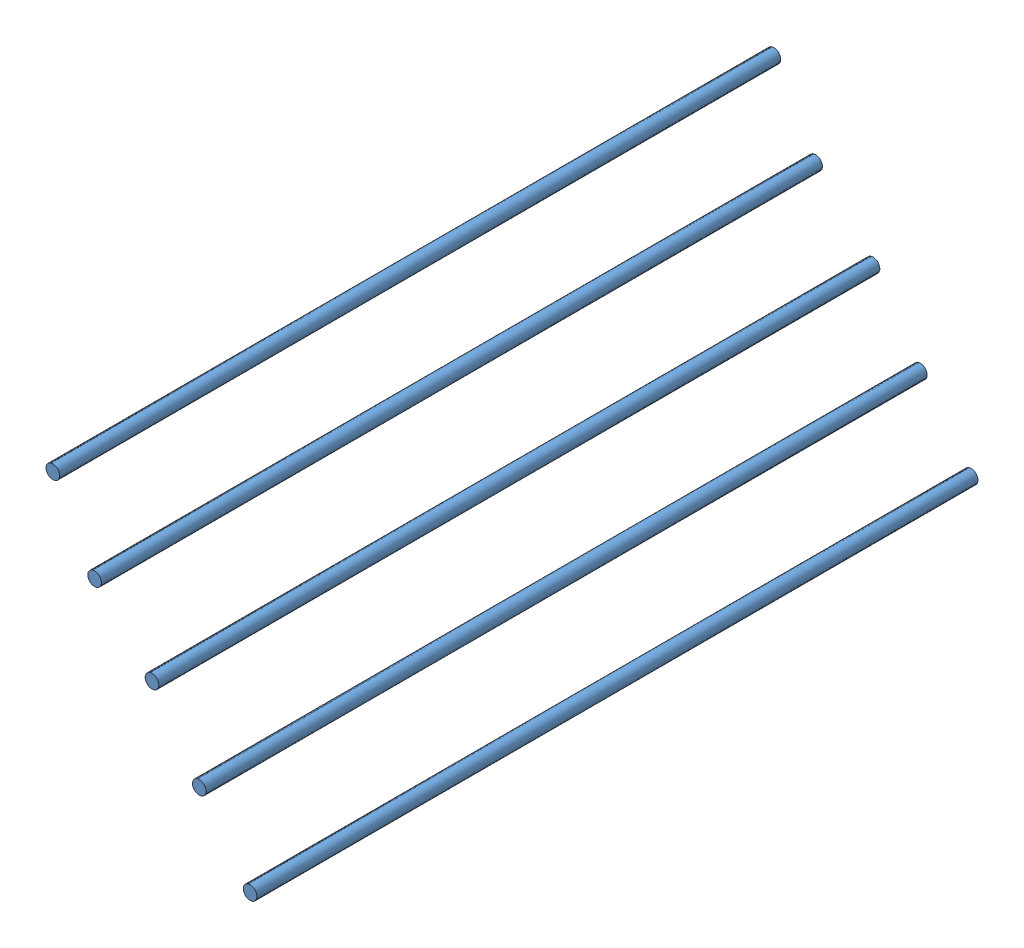
SolidWorks assembly Assem2, configuration Default. Lengths in mm.
Overall size (587.1 777.76 2006.6).
5 component instances, 1 part files, 13 mates.
Components (placement in the parent):
- Bed Rods-2: Bed Rods [Default] at (-321.4368 330.2566 -592.6398) x (0.825033 -0.565084 0) z (0 0 1) size (38.1 38.1 2006.6)
- Bed Rods-3: Bed Rods [Default] at (-179.9167 147.506 -592.6398) size (38.1 38.1 2006.6)
- Bed Rods-4: Bed Rods [Default] at (-612.8124 687.2971 -592.6398) size (38.1 38.1 2006.6)
- Bed Rods-5: Bed Rods [Default] at (-728.9154 887.1616 -592.6398) size (38.1 38.1 2006.6)
- Bed Rods-6: Bed Rods [Default] at (-453.0234 520.2846 -592.6398) x (0.999913 -0.013213 0) z (0 0 1) size (38.1 38.1 2006.6)
Mates (geometry in assembly coordinates):
- Coincident10: coincident aligned: plane of Bed Rods-5 through (-728.9154 887.1616 1413.9602) normal (0 0 1); plane of Bed Rods-4 through (-612.8124 687.2971 1413.9602) normal (0 0 1)
- Coincident11: coincident aligned: plane of Bed Rods-5 through (-728.9154 887.1616 1413.9602) normal (0 0 1); plane of Bed Rods-6 through (-453.0234 520.2846 1413.9602) normal (0 0 1)
- Coincident12: coincident aligned: plane of Bed Rods-5 through (-728.9154 887.1616 1413.9602) normal (0 0 1); circle of Bed Rods-2
- Coincident13: coincident aligned: plane of Bed Rods-5 through (-728.9154 887.1616 1413.9602) normal (0 0 1); plane of Bed Rods-2 through (-321.4368 330.2566 1413.9602) normal (0 0 1)
- Coincident14: coincident aligned: plane of Bed Rods-5 through (-728.9154 887.1616 1413.9602) normal (0 0 1); plane of Bed Rods-3 through (-179.9167 147.506 1413.9602) normal (0 0 1)
- Distance10: distance = 193.04 mm: cylinder of Bed Rods-3 through (-179.9167 147.506 1413.9602) axis (0 0 -1) radius 19.05; cylinder of Bed Rods-2 through (-321.4368 330.2566 1413.9602) axis (0 0 -1) radius 19.05
- Distance11: distance = 193.04 mm: cylinder of Bed Rods-2 through (-321.4368 330.2566 1413.9602) axis (0 0 -1) radius 19.05; cylinder of Bed Rods-6 through (-453.0234 520.2846 1413.9602) axis (0 0 -1) radius 19.05
- Distance12: distance = 193.04 mm: cylinder of Bed Rods-6 through (-453.0234 520.2846 1413.9602) axis (0 0 -1) radius 19.05; cylinder of Bed Rods-4 through (-612.8124 687.2971 1413.9602) axis (0 0 -1) radius 19.05
- Distance13: distance = 193.04 mm: cylinder of Bed Rods-4 through (-612.8124 687.2971 1413.9602) axis (0 0 -1) radius 19.05; cylinder of Bed Rods-5 through (-728.9154 887.1616 1413.9602) axis (0 0 -1) radius 19.05
- Coincident19: coincident aligned: plane of Bed Rods-3 through (-179.9167 147.506 -592.6398) normal (0 0 -1); plane of Bed Rods-2 through (-321.4368 330.2566 -592.6398) normal (0 0 -1)
- Coincident20: coincident aligned: plane of Bed Rods-3 through (-179.9167 147.506 -592.6398) normal (0 0 -1); plane of Bed Rods-6 through (-453.0234 520.2846 -592.6398) normal (0 0 -1)
- Coincident21: coincident aligned: plane of Bed Rods-3 through (-179.9167 147.506 -592.6398) normal (0 0 -1); plane of Bed Rods-4 through (-612.8124 687.2971 -592.6398) normal (0 0 -1)
- Coincident22: coincident aligned: plane of Bed Rods-3 through (-179.9167 147.506 -592.6398) normal (0 0 -1); plane of Bed Rods-5 through (-728.9154 887.1616 -592.6398) normal (0 0 -1)
